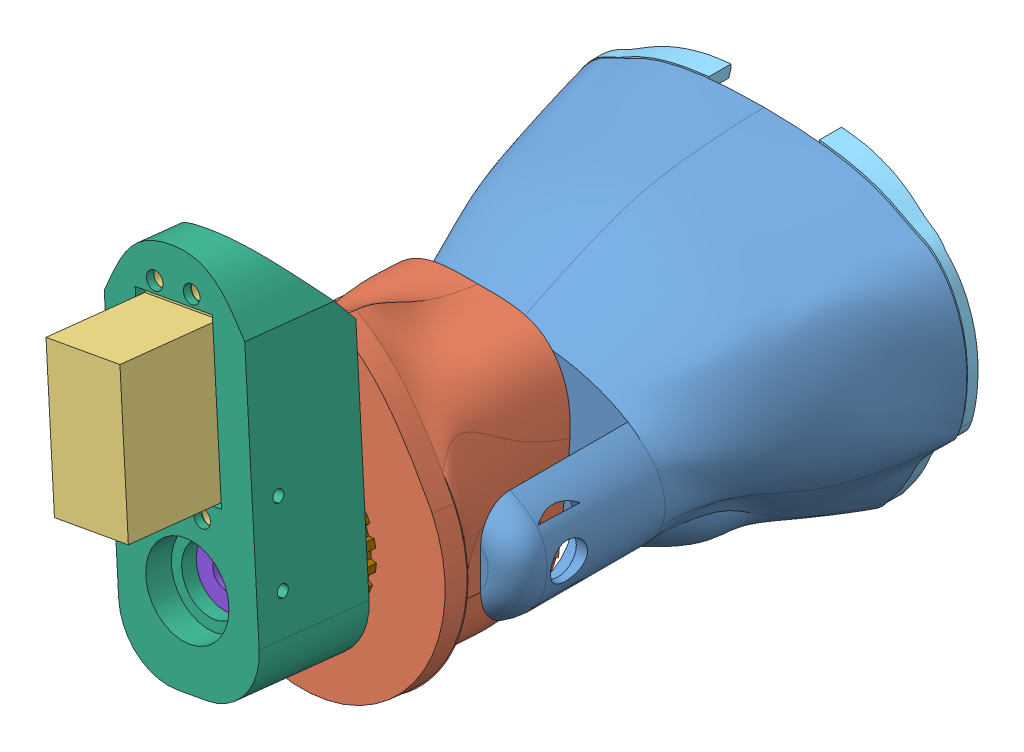
SolidWorks assembly neck full assm, configuration Default. Lengths in mm.
Overall size (124.6 132.1 194.2).
13 component instances, 10 part files, 4 mates.
Components (placement in the parent):
- Neck assm-1: Neck assm [Default-_flexible2] at origin size (124.17 98.69 135) (flexible)
  - mainneck-1: mainneck [Default] at origin size (124.17 91.01 111.8)
  - Neck angle top-1: Neck angle top [Default] at (0 35.8475 121.8243) x (-1 0 0) z (0 -0.106303 -0.994334) size (74.22 85.05 43)
  - servo standard-1: servo standard [Default] at (-5.4798 60.6917 87.9916) x (1 0 0) z (0 -0.994334 0.106303) size (49 20 52)
  - servo horn 1-1: servo horn 1 [Default] at (-35.55 32.8512 76.7017) x (0 0.030091 -0.999547) z (1 0 0) size (38.7 12.89 6.25)
- neck bottom shim-1: neck bottom shim [Default] at (0.3391 6.0031 0) x (0.999989 0.004745 0) z (0 0 -1) size (124.17 91.01 115.78)
- neck gearbox assm-1: neck gearbox assm [Default-_flexible2] at (-4.6223 67.0274 153.6904) x (-0.165083 0.980691 -0.104844) z (0 -0.106303 -0.994334) size (96.66 46 85) (flexible)
  - neckrot-1: neckrot [Default] at origin size (96.66 38 30)
  - neckrot_top-1: neckrot_top [Default] at (0 0 30) size (96.66 38 30) (hidden)
  - neckrotlarge-2: neckrotlarge [Default] at (3.0832 -0.1351 29.8) x (0.555595 -0.831453 0) z (0 0 -1) size (32.81 32.81 10)
  - bearing-1: bearing [Default] at (-28 0 18) x (-0.374205 -0.927346 0) z (0 0 -1) size (22 22 7)
  - servo standard-1: servo standard [Default] at (31.3832 -0.1351 -4.0202) x (0 0 -1) z (-1 0 0) size (49 20 52)
  - neckrotlarge mount-1: neckrotlarge mount [Default] at (-28 0 18) x (0.165083 -0.98628 0) z (0 0 1) size (32.81 32.81 17)
Mates (geometry in assembly coordinates):
- Coincident34: coincident anti-aligned: plane of Neck assm-1/mainneck-1 through (-41.7528 12.1247 0) normal (0 0 -1); plane of neck bottom shim-1 through (42.06 12.8289 0) normal (0 0 1)
- Concentric1: concentric aligned: circle of neck gearbox assm-1/neckrotlarge mount-1; circle of Neck assm-1/Neck angle top-1
- Concentric2: concentric anti-aligned: circle of Neck assm-1/Neck angle top-1; circle of neck gearbox assm-1/neckrotlarge mount-1
- Coincident35: coincident anti-aligned: plane of Neck assm-1/Neck angle top-1 through (-11.6798 75.7379 117.5597) normal (0 0.106303 0.994334); plane of neck gearbox assm-1/neckrotlarge mount-1 through (0 35.8475 121.8243) normal (0 -0.106303 -0.994334)
